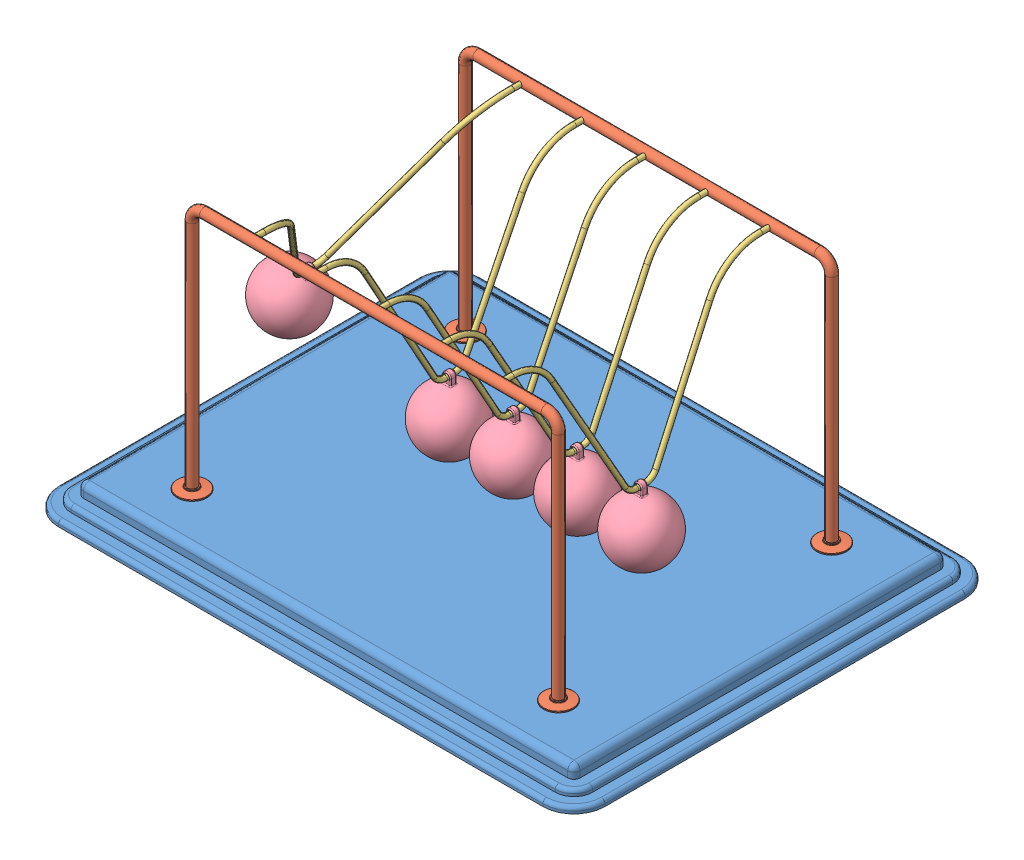
SolidWorks assembly Newtons Cradle NewtonsCradle 0246, configuration Default. Lengths in mm.
Overall size (440 222 340).
13 component instances, 4 part files, 34 mates.
Components (placement in the parent):
- Base 199,35170178282-1: Base 199,35170178282 [Default] at (-16.2968 -4.1587 11.425) size (440 20 340)
- frame NewtonsCradle 0246-1: frame NewtonsCradle 0246 [Default] at (-16.2968 144.4547 -98.575) size (319 202 24)
- frame NewtonsCradle 0246-2: frame NewtonsCradle 0246 [Default] at (-16.2968 144.4547 121.425) x (-1 0 0) z (0 0 -1) size (319 202 24)
- Hanging thing NewtonsCradle 0246-1: Hanging thing NewtonsCradle 0246 [Default] at (-157.6326 134.1825 11.425) x (0 0 1) z (-0.859985 0.510319 0) size (220 129 4)
- Hanging thing NewtonsCradle 0246-2: Hanging thing NewtonsCradle 0246 [Default] at (-66.576 122.8418 11.425) x (0 0 1) z (-0.999994 0.003446 0) size (220 129 4)
- Hanging thing NewtonsCradle 0246-3: Hanging thing NewtonsCradle 0246 [Default] at (-15.6923 122.8436 11.425) x (0 0 1) z (-0.999972 -0.007464 0) size (220 129 4)
- Hanging thing NewtonsCradle 0246-4: Hanging thing NewtonsCradle 0246 [Default] at (35.2213 122.8555 11.425) x (0 0 1) z (-0.999824 -0.018742 0) size (220 129 4)
- Hanging thing NewtonsCradle 0246-5: Hanging thing NewtonsCradle 0246 [Default] at (86.0287 122.8747 11.425) x (0 0 1) z (-0.999588 -0.028711 0) size (220 129 4)
- Sphere NewtonsCradle 0246-1: Sphere NewtonsCradle 0246 [Default] at (-195.3962 70.5436 11.425) x (0.859985 -0.510319 0) z (0 0 1) size (50 58.5 50)
- Sphere NewtonsCradle 0246-2: Sphere NewtonsCradle 0246 [Default] at (88.1533 48.9052 11.425) x (0.999588 0.028711 0) z (0 0 1) size (50 58.5 50)
- Sphere NewtonsCradle 0246-3: Sphere NewtonsCradle 0246 [Default] at (-15.14 48.8456 11.425) x (0.999972 0.007464 0) z (0 0 1) size (50 58.5 50)
- Sphere NewtonsCradle 0246-4: Sphere NewtonsCradle 0246 [Default] at (36.6081 48.8685 11.425) x (0.999824 0.018742 0) z (0 0 1) size (50 58.5 50)
- Sphere NewtonsCradle 0246-5: Sphere NewtonsCradle 0246 [Default] at (-66.831 48.8422 11.425) x (0.999994 -0.003446 0) z (0 0 1) size (50 58.5 50)
Mates (geometry in assembly coordinates):
- Coincident1: coincident anti-aligned: plane of Base-1 through (-211.2968 5.8413 156.425) normal (0 1 0); plane of frame-2 through (-175.7968 5.8413 121.425) normal (0 -1 0)
- Coincident2: coincident anti-aligned: plane of Base-1 through (-211.2968 5.8413 156.425) normal (0 1 0); plane of frame-1 through (143.2032 5.8413 -98.575) normal (0 -1 0)
- Concentric1: concentric anti-aligned: cylinder of frame-1 through (-116.2968 203.8413 -94.575) axis (0 0 -1) radius 2; cylinder of frame-2 through (-116.2968 203.8413 117.425) axis (0 0 1) radius 2
- Concentric2: concentric anti-aligned: cylinder of frame-1 through (83.7032 203.8413 -94.575) axis (0 0 -1) radius 2; cylinder of frame-2 through (83.7032 203.8413 117.425) axis (0 0 1) radius 2
- Distance1: distance = 60 mm: plane of frame-1 through (-16.2968 144.4547 -98.575) normal (0 0 1); line of Base-1 through (-211.2968 -12.1587 -158.575) axis (1 0 0)
- Distance2: distance = 60 mm: line of Base-1 through (178.7032 -12.1587 181.425) axis (-1 0 0); plane of frame-2 through (-16.2968 144.4547 121.425) normal (0 0 -1)
- Distance3: distance = 220 mm: plane of frame-2 through (-16.2968 144.4547 121.425) normal (-1 0 0); line of Base-1 through (-236.2968 -12.1587 156.425) axis (0 0 -1)
- Concentric3: concentric anti-aligned: cylinder of frame-1 through (-116.2968 203.8413 -94.575) axis (0 0 -1) radius 2; cylinder of Hanging thing-1 through (-116.2968 203.8413 111.425) axis (0 0 1) radius 2
- Concentric4: concentric anti-aligned: cylinder of frame-1 through (-116.2968 203.8413 -94.575) axis (0 0 -1) radius 2; cylinder of Hanging thing-1 through (-116.2968 203.8413 -98.575) axis (0 0 1) radius 2
- Concentric5: concentric aligned: cylinder of frame-2 through (-66.2968 203.8413 117.425) axis (0 0 1) radius 2; cylinder of Hanging thing-2 through (-66.2968 203.8413 111.425) axis (0 0 1) radius 2
- Concentric6: concentric aligned: cylinder of frame-2 through (-16.2968 203.8413 117.425) axis (0 0 1) radius 2; cylinder of Hanging thing-3 through (-16.2968 203.8413 111.425) axis (0 0 1) radius 2
- Concentric7: concentric aligned: cylinder of frame-2 through (33.7032 203.8413 117.425) axis (0 0 1) radius 2; cylinder of Hanging thing-4 through (33.7032 203.8413 111.425) axis (0 0 1) radius 2
- Concentric8: concentric aligned: cylinder of frame-2 through (83.7032 203.8413 117.425) axis (0 0 1) radius 2; cylinder of Hanging thing-5 through (83.7032 203.8413 111.425) axis (0 0 1) radius 2
- Coincident5: coincident anti-aligned: plane of frame-2 through (83.7032 203.8413 121.425) normal (0 0 -1); plane of Hanging thing-5 through (83.7032 203.8413 121.425) normal (0 0 1)
- Coincident6: coincident anti-aligned: plane of frame-2 through (33.7032 203.8413 121.425) normal (0 0 -1); plane of Hanging thing-4 through (33.7032 203.8413 121.425) normal (0 0 1)
- Coincident7: coincident anti-aligned: plane of frame-2 through (-16.2968 203.8413 121.425) normal (0 0 -1); plane of Hanging thing-3 through (-16.2968 203.8413 121.425) normal (0 0 1)
- Coincident8: coincident anti-aligned: plane of frame-2 through (-66.2968 203.8413 121.425) normal (0 0 -1); plane of Hanging thing-2 through (-66.2968 203.8413 121.425) normal (0 0 1)
- Coincident9: coincident anti-aligned: plane of frame-2 through (-116.2968 203.8413 121.425) normal (0 0 -1); plane of Hanging thing-1 through (-116.2968 203.8413 121.425) normal (0 0 1)
- Concentric9: concentric anti-aligned: cylinder of Hanging thing-1 through (-117.0163 78.8434 7.925) axis (0 0 1) radius 2; cylinder of Sphere-1 through (-117.0163 78.8434 13.925) axis (0 0 -1) radius 2
- Concentric13: concentric anti-aligned: cylinder of Hanging thing-2 through (-66.7276 78.842 7.925) axis (0 0 1) radius 2; cylinder of Sphere-5 through (-66.7276 78.842 13.925) axis (0 0 -1) radius 2
- Concentric15: concentric anti-aligned: cylinder of Hanging thing-3 through (-15.3639 78.8448 7.925) axis (0 0 1) radius 2; cylinder of Sphere-3 through (-15.3639 78.8448 13.925) axis (0 0 -1) radius 2
- Concentric16: concentric anti-aligned: cylinder of Hanging thing-5 through (87.292 78.8928 7.925) axis (0 0 1) radius 2; cylinder of Sphere-2 through (87.292 78.8928 13.925) axis (0 0 -1) radius 2
- Concentric17: concentric anti-aligned: cylinder of Hanging thing-4 through (36.0459 78.8632 7.925) axis (0 0 1) radius 2; cylinder of Sphere-4 through (36.0459 78.8632 13.925) axis (0 0 -1) radius 2
- Parallel1: parallel anti-aligned: plane of Hanging thing-1; plane of Sphere-1
- Coincident22: coincident anti-aligned: plane of Hanging thing-1; plane of Sphere-1
- Coincident12: coincident aligned: plane of Hanging thing-2 through (-66.576 122.8418 11.425) normal (0 0 1); plane of Sphere-5 through (-66.831 48.8422 11.425) normal (0 0 1)
- Coincident10: coincident aligned: plane of Hanging thing-1 through (-116.763 122.8426 11.425) normal (0 0 1); plane of Sphere-1 through (-118.5806 48.8842 11.425) normal (0 0 1)
- Coincident13: coincident anti-aligned: plane of Hanging thing-2 through (-66.576 122.8418 11.425) normal (-0.999994 0.003446 0); plane of Sphere-5 through (-66.831 48.8422 11.425) normal (0.999994 -0.003446 0)
- Coincident14: coincident anti-aligned: plane of Hanging thing-3 through (-15.6923 122.8436 11.425) normal (-0.999972 -0.007464 0); plane of Sphere-3 through (-15.14 48.8456 11.425) normal (0.999972 0.007464 0)
- Coincident15: coincident aligned: plane of Hanging thing-3 through (-15.6923 122.8436 11.425) normal (0 0 1); plane of Sphere-3 through (-15.14 48.8456 11.425) normal (0 0 1)
- Coincident18: coincident aligned: plane of Hanging thing-4 through (35.2213 122.8555 11.425) normal (0 0 1); plane of Sphere-4 through (36.6081 48.8685 11.425) normal (0 0 1)
- Coincident19: coincident anti-aligned: plane of Hanging thing-4 through (35.2213 122.8555 11.425) normal (-0.999824 -0.018742 0); plane of Sphere-4 through (36.6081 48.8685 11.425) normal (0.999824 0.018742 0)
- Coincident20: coincident anti-aligned: plane of Hanging thing-5 through (86.0287 122.8747 11.425) normal (-0.999588 -0.028711 0); plane of Sphere-2 through (88.1533 48.9052 11.425) normal (0.999588 0.028711 0)
- Coincident21: coincident aligned: plane of Hanging thing-5 through (86.0287 122.8747 11.425) normal (0 0 1); plane of Sphere-2 through (88.1533 48.9052 11.425) normal (0 0 1)
